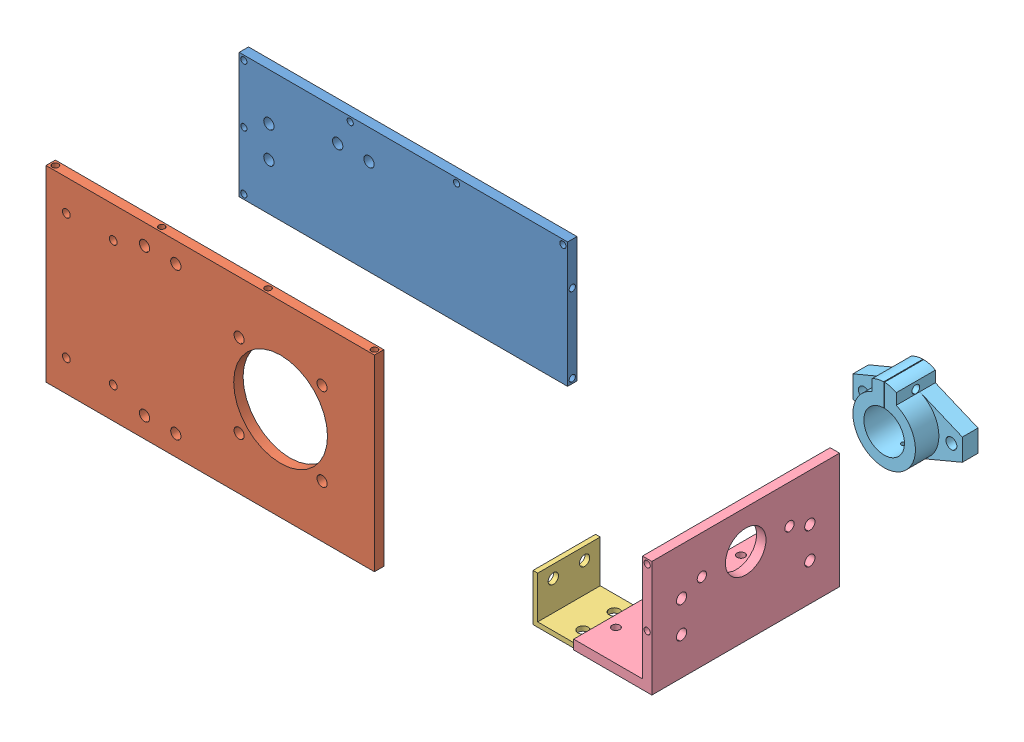
SolidWorks assembly 装配体1, configuration 默认. Lengths in mm.
Overall size (500.42 241.41 132.5).
5 component instances, 5 part files, 0 mates.
Components (placement in the parent):
- 底板-1: 底板 [Default] at (-4.3672 -23.5157 207) size (210 80 6)
- 板1-1: 板1 [默认] at (-79.8794 -164.926 210) size (210 120 6)
- 固定角钢-1: 固定角钢 [默认] at (98.4979 -186.474 193) size (30 30 40)
- 直角板-1: 直角板 [默认] at (169.5047 -167.5138 193) size (50 74 120)
- 轴承支座26-1: 轴承支座26 [默认] at (235.5426 -54.8472 120.5) size (70 47.49 25)
